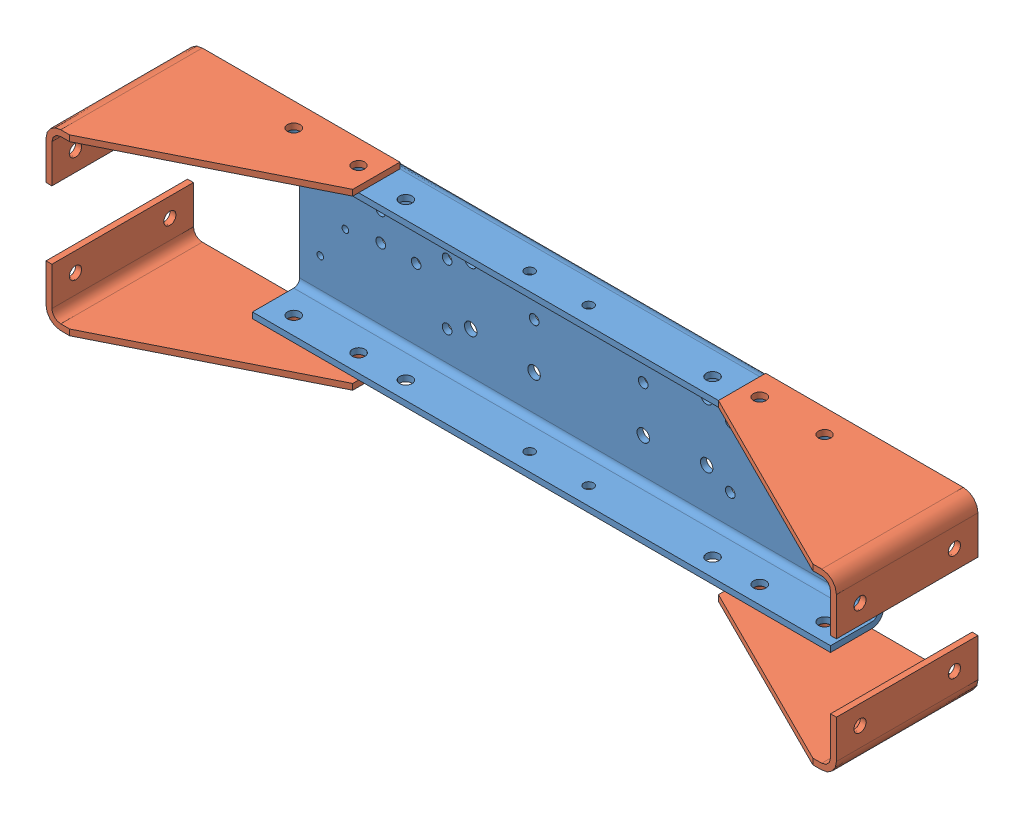
SolidWorks assembly SUB-1700-068, configuration Collapsed - No fasteners. Lengths in mm.
Overall size (850.9 187.32 165.1).
21 component instances, 4 part files, 64 mates.
Components (placement in the parent):
- 2504-CC2-1: 2504-CC2 [Default] at (0 0 -38.1) x (-1 0 0) z (0 0 -1)
- 2506-CC2-7: 2506-CC2 [2506-CC2-001] at (425.45 93.6625 0) x (-1 0 0) z (0 0 -1)
- 2506-CC2-8: 2506-CC2 [2506-CC2-001] at (-425.45 -93.6625 0) x (1 0 0) z (0 0 -1)
- 2506-CC2-9: 2506-CC2 [2506-CC2-002] at (-425.45 93.6625 0)
- 2506-CC2-10: 2506-CC2 [2506-CC2-002] at (425.45 -93.6625 0) x (-1 0 0) z (0 0 1)
- 08130XXXFH8Y-8: 08130XXXFH8Y [08130125FH8Y] at (-215.9 -93.6625 0) x (0.866025 0 0.5) z (0 -1 0) (suppressed, hidden)
- 08130XXXFH8Y-3: 08130XXXFH8Y [08130125FH8Y] at (215.9 93.6625 0) x (0.866025 0 -0.5) z (0 1 0) (suppressed, hidden)
- 08130XXXFH8Y-6: 08130XXXFH8Y [08130125FH8Y] at (215.9 -93.6625 0) x (0.866025 0 0.5) z (0 -1 0) (suppressed, hidden)
- 08130XXXFH8Y-1: 08130XXXFH8Y [08130125FH8Y] at (-215.9 93.6625 0) x (0 0 -1) z (0 1 0) (suppressed, hidden)
- 08130XXXFH8Y-7: 08130XXXFH8Y [08130125FH8Y] at (-285.75 -93.6625 0) x (0.866025 0 0.5) z (0 -1 0) (suppressed, hidden)
- 08130XXXFH8Y-2: 08130XXXFH8Y [08130125FH8Y] at (-285.75 93.6625 0) x (0 0 -1) z (0 1 0) (suppressed, hidden)
- 08130XXXFH8Y-4: 08130XXXFH8Y [08130125FH8Y] at (285.75 93.6625 0) x (0.866025 0 -0.5) z (0 1 0) (suppressed, hidden)
- 08130XXXFH8Y-5: 08130XXXFH8Y [08130125FH8Y] at (285.75 -93.6625 0) x (0.866025 0 0.5) z (0 -1 0) (suppressed, hidden)
- XXXXFLN8Y-7: XXXXFLN8Y [0813FLN8Y] at (-285.75 -80.9625 0) x (0 0 1) z (0 1 0) (suppressed, hidden)
- XXXXFLN8Y-2: XXXXFLN8Y [0813FLN8Y] at (-215.9 80.9625 0) x (0 0 -1) z (0 -1 0) (suppressed, hidden)
- XXXXFLN8Y-1: XXXXFLN8Y [0813FLN8Y] at (-285.75 80.9625 0) x (0.866025 0 0.5) z (0 -1 0) (suppressed, hidden)
- XXXXFLN8Y-8: XXXXFLN8Y [0813FLN8Y] at (-215.9 -80.9625 0) x (0 0 1) z (0 1 0) (suppressed, hidden)
- XXXXFLN8Y-3: XXXXFLN8Y [0813FLN8Y] at (215.9 80.9625 0) x (0.866025 0 0.5) z (0 -1 0) (suppressed, hidden)
- XXXXFLN8Y-6: XXXXFLN8Y [0813FLN8Y] at (215.9 -80.9625 0) x (0.866025 0 0.5) z (0 1 0) (suppressed, hidden)
- XXXXFLN8Y-4: XXXXFLN8Y [0813FLN8Y] at (285.75 80.9625 0) x (0.866025 0 0.5) z (0 -1 0) (suppressed, hidden)
- XXXXFLN8Y-5: XXXXFLN8Y [0813FLN8Y] at (285.75 -80.9625 0) x (0.866025 0 0.5) z (0 1 0) (suppressed, hidden)
Mates (geometry in assembly coordinates):
- Distance1: distance = 38.1 mm anti-aligned: plane of 2504-CC2-1 through (0 0 -38.1) normal (0 0 -1)
- Coincident53: coincident anti-aligned: unknown of 2504-CC2-1
- Coincident78: coincident aligned: unknown of 2504-CC2-1
- Concentric9: concentric anti-aligned: cylinder of ?; cylinder of ?
- Concentric10: concentric anti-aligned: cylinder of ?; cylinder of ?
- Coincident108: coincident anti-aligned: unknown of 2504-CC2-1
- Coincident109: coincident anti-aligned: unknown of 2504-CC2-1
- Concentric11: concentric anti-aligned: cylinder of ?; cylinder of ?
- Concentric12: concentric anti-aligned: cylinder of ?; cylinder of ?
- Coincident110: coincident anti-aligned: unknown of 2504-CC2-1
- Coincident111: coincident anti-aligned: unknown of 2504-CC2-1
- Concentric13: concentric anti-aligned: cylinder of ?; cylinder of ?
- Concentric14: concentric anti-aligned: cylinder of ?; cylinder of ?
- Coincident112: coincident anti-aligned: unknown of 2504-CC2-1
- Coincident113: coincident anti-aligned: unknown of 2504-CC2-1
- Concentric15: concentric anti-aligned: cylinder of ?; cylinder of ?
- Coincident114: coincident anti-aligned: unknown of 2504-CC2-1
- Concentric16: concentric anti-aligned: cylinder of ?; cylinder of ?
- Coincident115: coincident anti-aligned: unknown of 2504-CC2-1
- Parallel1: parallel: line of ?; plane of assembly
- Parallel2: parallel: line of ?; plane of assembly
- Parallel3: parallel: line of ?; plane of assembly
- Parallel4: parallel: line of ?; plane of assembly
- Parallel5: parallel: line of ?; plane of assembly
- Parallel6: parallel: line of ?; plane of assembly
- Parallel7: parallel: line of ?; plane of assembly
- Parallel8: parallel: line of ?; plane of assembly
- Parallel9: parallel: line of ?; plane of assembly
- Parallel10: parallel: line of ?; plane of assembly
- Parallel11: parallel: line of ?; plane of assembly
- Parallel12: parallel: line of ?; plane of assembly
- Parallel13: parallel: line of ?; plane of assembly
- Parallel14: parallel: line of ?; plane of assembly
- Parallel15: parallel: line of ?; plane of assembly
- Parallel16: parallel: line of ?; plane of assembly
- Coincident116: coincident anti-aligned: plane of ?; plane of assembly
- Distance2: distance = 425.45 mm anti-aligned: plane of ?; plane of assembly
- Distance3: distance = 93.6625 mm aligned: plane of ?; plane of assembly
- Coincident117: coincident anti-aligned: plane of ?; plane of assembly
- Distance4: distance = 425.45 mm aligned: plane of ?; plane of assembly
- Distance5: distance = 93.6625 mm anti-aligned: plane of ?; plane of assembly
- Coincident119: coincident aligned: plane of ?; plane of assembly
- Distance6: distance = 425.45 mm aligned: plane of ?; plane of assembly
- Distance7: distance = 93.6625 mm aligned: plane of ?; plane of assembly
- Coincident120: coincident aligned: plane of ?; plane of assembly
- Distance8: distance = 425.45 mm anti-aligned: plane of ?; plane of assembly
- Distance9: distance = 93.6625 mm anti-aligned: plane of ?; plane of assembly
- Concentric17: concentric anti-aligned: circle of ?; circle of ?
- Concentric18: concentric anti-aligned: circle of ?; cylinder of ?
- Concentric19: concentric anti-aligned: circle of ?; cylinder of ?
- Concentric20: concentric anti-aligned: circle of ?; cylinder of ?
- Coincident121: coincident anti-aligned: plane of ?; plane of ?
- Coincident122: coincident anti-aligned: plane of ?; plane of ?
- Coincident123: coincident anti-aligned: plane of ?; plane of ?
- Concentric21: concentric anti-aligned: circle of ?; cylinder of ?
- Concentric22: concentric anti-aligned: circle of ?; cylinder of ?
- Coincident124: coincident anti-aligned: plane of ?; plane of ?
- Coincident125: coincident anti-aligned: plane of ?; plane of ?
- Concentric23: concentric anti-aligned: cylinder of ?; cylinder of ?
- Coincident126: coincident anti-aligned: plane of ?; plane of ?
- Concentric24: concentric anti-aligned: cylinder of ?; cylinder of ?
- Coincident127: coincident anti-aligned: plane of ?; plane of ?
- Coincident128: coincident anti-aligned: plane of ?; plane of ?
- Coincident129: coincident anti-aligned: 
